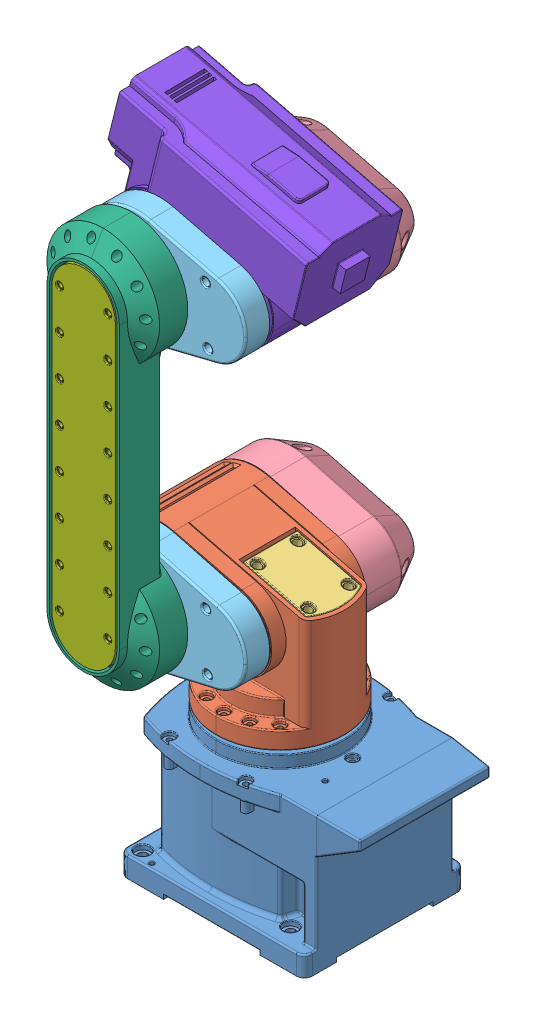
SolidWorks assembly movable step 3, configuration Default. Lengths in mm.
Overall size (419.73 809.8 303.13).
10 component instances, 8 part files, 27 mates.
Components (placement in the parent):
- Base.step-1: Base.step [Default] at (50.4601 21.8888 234.5287) size (280 185 200)
- Joint_1.step-1: Joint_1.step [Default] at (68.2167 333.4398 234.5287) size (242.75 189 160)
- Joint_1_top_cap.step-1: Joint_1_top_cap.step [Default] at (70.5148 316.8888 234.5287) x (1 0 0) z (0 1 0) size (91.2 70 52.34)
- Part3.step-1: Part3.step [Default] at (63.4179 21.928 234.5287) x (0.999815 -0.016322 -0.010154) z (0.010153 -0.000166 0.999948) size (205.53 137 83.39)
- Part4.step-1: Part4.step [Default] at (63.4179 21.928 234.5287) x (0.999815 -0.016322 -0.010154) z (0.010153 -0.000166 0.999948) size (205.37 137 45.97)
- Joint_2.step-1: Joint_2.step [Default] at (-21.7667 647.378 238.6434) x (0 -0.999953 -0.009698) z (0.003009 -0.009698 0.999948) size (490.3 140.11 64.56)
- joint_2_cap.step-1: joint_2_cap.step [Default] at (-275.8903 144.2787 234.5287) x (0.296333 -0.955031 -0.010154) z (0.003009 -0.009698 0.999948) size (415.27 184.72 18.75)
- Part3.step-2: Part3.step [Default] at (68.4534 373.4102 234.5287) x (0.999948 0.000764 -0.010154) z (0.010154 0.000008 0.999948) size (205.53 137 83.39)
- Part4.step-2: Part4.step [Default] at (68.4534 373.4102 234.5287) x (0.999948 0.000764 -0.010154) z (0.010154 0.000008 0.999948) size (205.37 137 45.97)
- Part5.step-1: Part5.step [Default] at (24.1084 630.1919 238.2942) x (0.970756 -0.239852 -0.010154) z (0.009858 -0.002436 0.999948) size (270.42 212 122.27)
Mates (geometry in assembly coordinates):
- Concentric1: concentric aligned: cylinder of Base.step-1 through (68.2167 206.8888 234.5287) axis (0 -1 0) radius 80; cylinder of Joint_1.step-1 through (68.2167 222.8888 234.5287) axis (0 -1 0) radius 69
- Coincident1: coincident anti-aligned: plane of Base.step-1 through (68.2167 196.8888 234.5287) normal (0 1 0); plane of Joint_1.step-1 through (68.2167 196.8888 234.5287) normal (0 -1 0)
- Parallel1: parallel aligned: plane of Base.step-1 through (198.2167 111.8888 319.5287) normal (0 0 1); plane of Joint_1.step-1 through (68.2167 333.4398 274.5287) normal (0 0 1)
- Coincident2: coincident anti-aligned: plane of Joint_1.step-1 through (68.2167 316.8888 234.5287) normal (0 1 0); plane of Joint_1_top_cap.step-1 through (70.5148 316.8888 234.5287) normal (0 -1 0)
- Concentric3: concentric aligned: cylinder of Joint_1.step-1 through (68.2167 385.8888 234.5287) axis (0 -1 0) radius 75; cylinder of Joint_1_top_cap.step-1 through (68.2167 470.6805 234.5287) axis (0 -1 0) radius 75.4393
- Parallel2: parallel anti-aligned: plane of Joint_1.step-1 through (52.0118 385.8888 269.5287) normal (1 0 0); plane of Joint_1_top_cap.step-1 through (55.8099 470.6805 201.0287) normal (-1 0 0)
- Coincident3: coincident anti-aligned: plane of Joint_1.step-1 through (68.2167 333.4398 174.5287) normal (0 0 -1); plane of Part3.step-1 through (68.2167 315.8888 174.5287) normal (0 0 1)
- Concentric4: concentric anti-aligned: cylinder of Joint_1.step-1 through (68.2167 315.8888 274.5287) axis (0 0 -1) radius 48.4134; cylinder of Part3.step-1 through (68.2167 315.8888 94.5287) axis (0 0 1) radius 46.9225
- Tangent1: tangent aligned: cylinder of Joint_1.step-1 through (-21.7787 315.8888 274.5287) axis (0 0 -1) radius 70; cylinder of Part3.step-1 through (-21.4511 317.3526 94.5287) axis (0 0 1) radius 68.5
- Coincident4: coincident anti-aligned: plane of Joint_1.step-1 through (68.2167 333.4398 294.5287) normal (0 0 1); plane of Part4.step-1 through (68.2167 315.8888 294.5287) normal (0 0 -1)
- Concentric6: concentric aligned: cylinder of Joint_1.step-1 through (68.2167 315.8888 274.5287) axis (0 0 -1) radius 48.4134; cylinder of Part4.step-1 through (68.2167 315.8888 324.5287) axis (0 0 -1) radius 46.9225
- Tangent2: tangent aligned: cylinder of Joint_1.step-1 through (-21.7787 315.8888 274.5287) axis (0 0 -1) radius 70; cylinder of Part4.step-1 through (-21.4511 317.3526 324.5287) axis (0 0 -1) radius 68.5
- Coincident5: coincident anti-aligned: plane of Part4.step-1 through (-21.7667 317.3577 329.5287) normal (0 0 1); plane of Joint_2.step-1 through (-21.7667 317.3577 329.5287) normal (0 0 -1)
- Concentric7: concentric aligned: cylinder of Part4.step-1 through (-21.7667 317.3577 339.5287) axis (0 0 -1) radius 30; cylinder of Joint_2.step-1 through (-21.7667 317.3577 339.5287) axis (0 0 -1) radius 30
- Parallel3: parallel aligned: plane of Base.step-1 through (198.2167 46.8888 134.5287) normal (1 0 0); plane of Joint_2.step-1 through (23.2333 667.3413 339.5287) normal (1 0 0)
- Concentric8: concentric anti-aligned: cylinder of Joint_2.step-1 through (-21.7667 317.3577 374.5287) axis (0 0 1) radius 42; cylinder of joint_2_cap.step-1 through (-21.7667 317.3577 389.0687) axis (0 0 -1) radius 39.5
- Coincident6: coincident anti-aligned: plane of Joint_2.step-1 through (-21.7667 667.3413 374.5287) normal (0 0 1); plane of joint_2_cap.step-1 through (-21.7667 317.3577 374.5287) normal (0 0 -1)
- Concentric9: concentric anti-aligned: cylinder of Joint_2.step-1 through (-21.7667 667.3413 374.5287) axis (0 0 1) radius 42; cylinder of joint_2_cap.step-1 through (-21.7667 667.3413 389.0687) axis (0 0 -1) radius 39.5
- Coincident7: coincident anti-aligned: plane of Joint_2.step-1 through (-21.7667 667.3413 329.5287) normal (0 0 -1); plane of Part4.step-2 through (-21.7667 667.3413 329.5287) normal (0 0 1)
- Concentric10: concentric aligned: cylinder of Joint_2.step-1 through (-21.7667 667.3413 339.5287) axis (0 0 -1) radius 30; cylinder of Part4.step-2 through (-21.7667 667.3413 339.5287) axis (0 0 -1) radius 30
- Concentric11: concentric anti-aligned: cylinder of Part4.step-2 through (68.2286 667.4101 324.5287) axis (0 0 -1) radius 46.9225; cylinder of Part5.step-1 through (68.2286 667.4101 174.5287) axis (0 0 1) radius 46.9225
- Coincident8: coincident anti-aligned: plane of Part4.step-2 through (68.2286 667.4101 294.5287) normal (0 0 -1); plane of Part5.step-1 through (68.2286 667.4101 294.5287) normal (0 0 1)
- Concentric12: concentric anti-aligned: cylinder of Part4.step-2 through (-21.4511 667.3415 324.5287) axis (0 0 -1) radius 68.5; cylinder of Part5.step-1 through (-21.4511 667.3415 174.5287) axis (0 0 1) radius 68.5
- Coincident9: coincident anti-aligned: plane of Part3.step-2 through (68.2286 667.4101 174.5287) normal (0 0 1); plane of Part5.step-1 through (68.2286 667.4101 174.5287) normal (0 0 -1)
- Concentric13: concentric aligned: cylinder of Part3.step-2 through (-21.4511 667.3415 94.5287) axis (0 0 1) radius 68.5; cylinder of Part5.step-1 through (-21.4511 667.3415 174.5287) axis (0 0 1) radius 68.5
- Tangent3: tangent aligned: cylinder of Part3.step-2 through (68.2286 667.4101 94.5287) axis (0 0 1) radius 46.9225; cylinder of Part5.step-1 through (68.2286 667.4101 174.5287) axis (0 0 1) radius 46.9225
- Parallel4: parallel aligned: plane of Joint_1.step-1 through (75.7423 363.8986 274.5287) normal (0.239864 0.970807 0); plane of Part5.step-1 through (-25.6032 811.0323 179.5287) normal (0.239864 0.970807 0)
